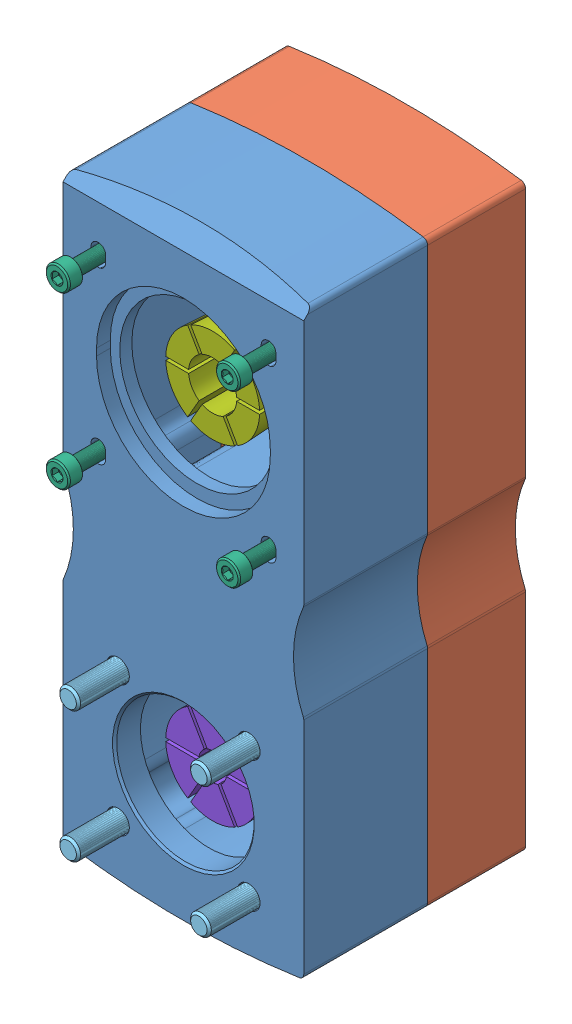
SolidWorks assembly Adapter parallel, configuration Default. Lengths in mm.
Overall size (70 173.5 79).
21 component instances, 8 part files, 30 mates.
Components (placement in the parent):
- 2607475 EAMM-U-70-D40-60P-96---(UT)-1: 2607475 EAMM-U-70-D40-60P-96---(UT) [Default] at (0 139 0) x (1 0 0) z (0 1 0) size (70 36 173.5)
- 2610112 EAMM-U-70-D40-___-173---(OT)-1: 2610112 EAMM-U-70-D40-___-173---(OT) [Default] at (0 139 -36) x (1 0 0) z (0 1 0) size (70 28.5 173.5)
- DIN-912 - M5x35(F)-1: DIN-912 - M5x35(F) [Default] at (29 -10 -58.5) x (1 0 0) z (0 1 0) size (8.5 40.23 8.5)
- DIN-912 - M5x35(F)-2: DIN-912 - M5x35(F) [Default] at (29 32.5 -58.5) x (1 0 0) z (0 1 0) size (8.5 40.23 8.5)
- DIN-912 - M5x35(F)-3: DIN-912 - M5x35(F) [Default] at (-29 -10 -58.5) x (1 0 0) z (0 1 0) size (8.5 40.23 8.5)
- DIN-912 - M5x35(F)-4: DIN-912 - M5x35(F) [Default] at (-29 32.5 -58.5) x (1 0 0) z (0 1 0) size (8.5 40.23 8.5)
- DIN-912 - M5x35(F)-5: DIN-912 - M5x35(F) [Default] at (0 133 -58.5) x (1 0 0) z (0 1 0) size (8.5 40.23 8.5)
- DIN 557 - M4-1: DIN 557 - M4 [Default] at (24.7487 120.7487 -3.4) x (0 0 -1) z (-0.707107 -0.707107 0) size (3.2 8.9 8.9)
- DIN 557 - M4-2: DIN 557 - M4 [Default] at (24.7487 71.2513 -3.4) x (0 0 -1) z (-0.707107 -0.707107 0) size (3.2 8.9 8.9)
- DIN 557 - M4-3: DIN 557 - M4 [Default] at (-24.7487 71.2513 -3.4) x (0 0 -1) z (-0.707107 -0.707107 0) size (3.2 8.9 8.9)
- DIN 557 - M4-4: DIN 557 - M4 [Default] at (-24.7487 120.7487 -3.4) x (0 0 -1) z (-0.707107 -0.707107 0) size (3.2 8.9 8.9)
- DIN-6912 - M6x18(F)-1: DIN-6912 - M6x18(F) [Default] at (19 19 -3.5) x (0 0 1) z (-1 0 0) size (22.29 10 10)
- DIN-6912 - M6x18(F)-2: DIN-6912 - M6x18(F) [Default] at (19 -19 -3.5) x (0 0 1) z (-1 0 0) size (22.29 10 10)
- DIN-6912 - M6x18(F)-3: DIN-6912 - M6x18(F) [Default] at (-19 19 -3.5) x (0 0 1) z (-1 0 0) size (22.29 10 10)
- DIN-6912 - M6x18(F)-4: DIN-6912 - M6x18(F) [Default] at (-19 -19 -3.5) x (0 0 1) z (-1 0 0) size (22.29 10 10)
- DIN-912 - M4x16(F)-1: DIN-912 - M4x16(F) [Default] at (24.7487 120.7487 8) x (1 0 0) z (0 -1 0) size (7 20.17 7)
- DIN-912 - M4x16(F)-2: DIN-912 - M4x16(F) [Default] at (24.7487 71.2513 8) x (1 0 0) z (0 -1 0) size (7 20.17 7)
- DIN-912 - M4x16(F)-3: DIN-912 - M4x16(F) [Default] at (-24.7487 71.2513 8) x (1 0 0) z (0 -1 0) size (7 20.17 7)
- DIN-912 - M4x16(F)-4: DIN-912 - M4x16(F) [Default] at (-24.7487 120.7487 8) x (1 0 0) z (0 -1 0) size (7 20.17 7)
- 2429534 EAMH-86-14-C27_3-1: 2429534 EAMH-86-14-C27_3 [Default] at (0 96 -48.5) x (0 0 1) z (-1 0 0) size (40.22 27.3 27.28)
- 2429531 EAMH-86-8-C27_3-1: 2429531 EAMH-86-8-C27_3 [Default] at (0 0 -48.5) x (0 0 1) z (-1 0 0) size (40.22 27.3 27.28)
Mates (geometry in assembly coordinates):
- Distance1: distance = 0 mm anti-aligned: plane of 2607475 EAMM-U-70-D40-60P-96---(UT)-1 through (0 139 -3.5) normal (0 0 -1); plane of DIN-6912 - M6x18(F)-1 through (19 19 -3.5) normal (0 0 1)
- Coincident1: coincident anti-aligned: line of 2607475 EAMM-U-70-D40-60P-96---(UT)-1 through (19 19 -50) axis (0 0 1); line of DIN-6912 - M6x18(F)-1 through (19 19 77.4) axis (0 0 -1)
- Angle3: planar angle = 0 rad aligned: plane of DIN-6912 - M6x18(F)-1 through (19 19 -3.5) normal (1 0 0); plane of 2607475 EAMM-U-70-D40-60P-96---(UT)-1 through (19 139 0) normal (1 0 0)
- Distance2: distance = 0 mm anti-aligned: plane of 2607475 EAMM-U-70-D40-60P-96---(UT)-1 through (0 139 -3.5) normal (0 0 -1); plane of DIN-6912 - M6x18(F)-2 through (19 -19 -3.5) normal (0 0 1)
- Coincident2: coincident anti-aligned: line of 2607475 EAMM-U-70-D40-60P-96---(UT)-1 through (19 -19 -50) axis (0 0 1); line of DIN-6912 - M6x18(F)-2 through (19 -19 77.4) axis (0 0 -1)
- Angle6: planar angle = 0 rad aligned: plane of DIN-6912 - M6x18(F)-2 through (19 -19 -3.5) normal (1 0 0); plane of 2607475 EAMM-U-70-D40-60P-96---(UT)-1 through (19 139 0) normal (1 0 0)
- Distance3: distance = 0 mm anti-aligned: plane of 2607475 EAMM-U-70-D40-60P-96---(UT)-1 through (0 139 -3.5) normal (0 0 -1); plane of DIN-6912 - M6x18(F)-3 through (-19 19 -3.5) normal (0 0 1)
- Coincident3: coincident anti-aligned: line of 2607475 EAMM-U-70-D40-60P-96---(UT)-1 through (-19 19 -50) axis (0 0 1); line of DIN-6912 - M6x18(F)-3 through (-19 19 77.4) axis (0 0 -1)
- Angle9: planar angle = 0 rad aligned: plane of DIN-6912 - M6x18(F)-3 through (-19 19 -3.5) normal (1 0 0); plane of 2607475 EAMM-U-70-D40-60P-96---(UT)-1 through (-19 139 0) normal (1 0 0)
- Distance4: distance = 0 mm anti-aligned: plane of 2607475 EAMM-U-70-D40-60P-96---(UT)-1 through (0 139 -3.5) normal (0 0 -1); plane of DIN-6912 - M6x18(F)-4 through (-19 -19 -3.5) normal (0 0 1)
- Coincident4: coincident anti-aligned: line of 2607475 EAMM-U-70-D40-60P-96---(UT)-1 through (-19 -19 -50) axis (0 0 1); line of DIN-6912 - M6x18(F)-4 through (-19 -19 77.4) axis (0 0 -1)
- Angle12: planar angle = 0 rad aligned: plane of DIN-6912 - M6x18(F)-4 through (-19 -19 -3.5) normal (1 0 0); plane of 2607475 EAMM-U-70-D40-60P-96---(UT)-1 through (-19 139 0) normal (1 0 0)
- Distance5: distance = 0 mm anti-aligned: plane of 2607475 EAMM-U-70-D40-60P-96---(UT)-1 through (0 139 8) normal (0 0 -1); plane of DIN-912 - M4x16(F)-1 through (24.7487 120.7487 8) normal (0 0 1)
- Coincident5: coincident anti-aligned: line of 2607475 EAMM-U-70-D40-60P-96---(UT)-1 through (24.7487 120.7487 -50) axis (0 0 1); line of DIN-912 - M4x16(F)-1 through (24.7487 120.7487 58) axis (0 0 -1)
- Angle15: planar angle = 0 rad aligned: plane of DIN-912 - M4x16(F)-1 through (24.7487 120.7487 8) normal (1 0 0); plane of 2607475 EAMM-U-70-D40-60P-96---(UT)-1 through (24.7487 139 0) normal (1 0 0)
- Distance6: distance = 0 mm anti-aligned: plane of 2607475 EAMM-U-70-D40-60P-96---(UT)-1 through (0 139 8) normal (0 0 -1); plane of DIN-912 - M4x16(F)-2 through (24.7487 71.2513 8) normal (0 0 1)
- Coincident6: coincident anti-aligned: line of 2607475 EAMM-U-70-D40-60P-96---(UT)-1 through (24.7487 71.2513 -50) axis (0 0 1); line of DIN-912 - M4x16(F)-2 through (24.7487 71.2513 58) axis (0 0 -1)
- Angle18: planar angle = 0 rad aligned: plane of DIN-912 - M4x16(F)-2 through (24.7487 71.2513 8) normal (1 0 0); plane of 2607475 EAMM-U-70-D40-60P-96---(UT)-1 through (24.7487 139 0) normal (1 0 0)
- Distance7: distance = 0 mm anti-aligned: plane of 2607475 EAMM-U-70-D40-60P-96---(UT)-1 through (0 139 8) normal (0 0 -1); plane of DIN-912 - M4x16(F)-3 through (-24.7487 71.2513 8) normal (0 0 1)
- Coincident7: coincident anti-aligned: line of 2607475 EAMM-U-70-D40-60P-96---(UT)-1 through (-24.7487 71.2513 -50) axis (0 0 1); line of DIN-912 - M4x16(F)-3 through (-24.7487 71.2513 58) axis (0 0 -1)
- Angle21: planar angle = 0 rad aligned: plane of DIN-912 - M4x16(F)-3 through (-24.7487 71.2513 8) normal (1 0 0); plane of 2607475 EAMM-U-70-D40-60P-96---(UT)-1 through (-24.7487 139 0) normal (1 0 0)
- Distance8: distance = 0 mm anti-aligned: plane of 2607475 EAMM-U-70-D40-60P-96---(UT)-1 through (0 139 8) normal (0 0 -1); plane of DIN-912 - M4x16(F)-4 through (-24.7487 120.7487 8) normal (0 0 1)
- Coincident8: coincident anti-aligned: line of 2607475 EAMM-U-70-D40-60P-96---(UT)-1 through (-24.7487 120.7487 -50) axis (0 0 1); line of DIN-912 - M4x16(F)-4 through (-24.7487 120.7487 58) axis (0 0 -1)
- Angle24: planar angle = 0 rad aligned: plane of DIN-912 - M4x16(F)-4 through (-24.7487 120.7487 8) normal (1 0 0); plane of 2607475 EAMM-U-70-D40-60P-96---(UT)-1 through (-24.7487 139 0) normal (1 0 0)
- Distance9: distance = 0 mm anti-aligned: plane of 2607475 EAMM-U-70-D40-60P-96---(UT)-1 through (0 139 -8.5) normal (0 0 -1); plane of 2429534 EAMH-86-14-C27_3-1 through (0 96 -8.5) normal (0 0 1)
- Coincident9: coincident anti-aligned: line of 2607475 EAMM-U-70-D40-60P-96---(UT)-1 through (0 96 -50) axis (0 0 1); line of 2429534 EAMH-86-14-C27_3-1 through (0 96 32.4) axis (0 0 -1)
- Angle27: planar angle = 0 rad aligned: plane of 2429534 EAMH-86-14-C27_3-1 through (0 96 -48.5) normal (1 0 0); plane of 2607475 EAMM-U-70-D40-60P-96---(UT)-1 through (0 139 0) normal (1 0 0)
- Distance10: distance = 0 mm anti-aligned: plane of 2607475 EAMM-U-70-D40-60P-96---(UT)-1 through (0 139 -8.5) normal (0 0 -1); plane of 2429531 EAMH-86-8-C27_3-1 through (0 0 -8.5) normal (0 0 1)
- Coincident10: coincident anti-aligned: line of 2607475 EAMM-U-70-D40-60P-96---(UT)-1 through (0 0 -50) axis (0 0 1); line of 2429531 EAMH-86-8-C27_3-1 through (0 0 32.4) axis (0 0 -1)
- Angle30: planar angle = 0 rad aligned: plane of 2429531 EAMH-86-8-C27_3-1 through (0 0 -48.5) normal (1 0 0); plane of 2607475 EAMM-U-70-D40-60P-96---(UT)-1 through (0 139 0) normal (1 0 0)
